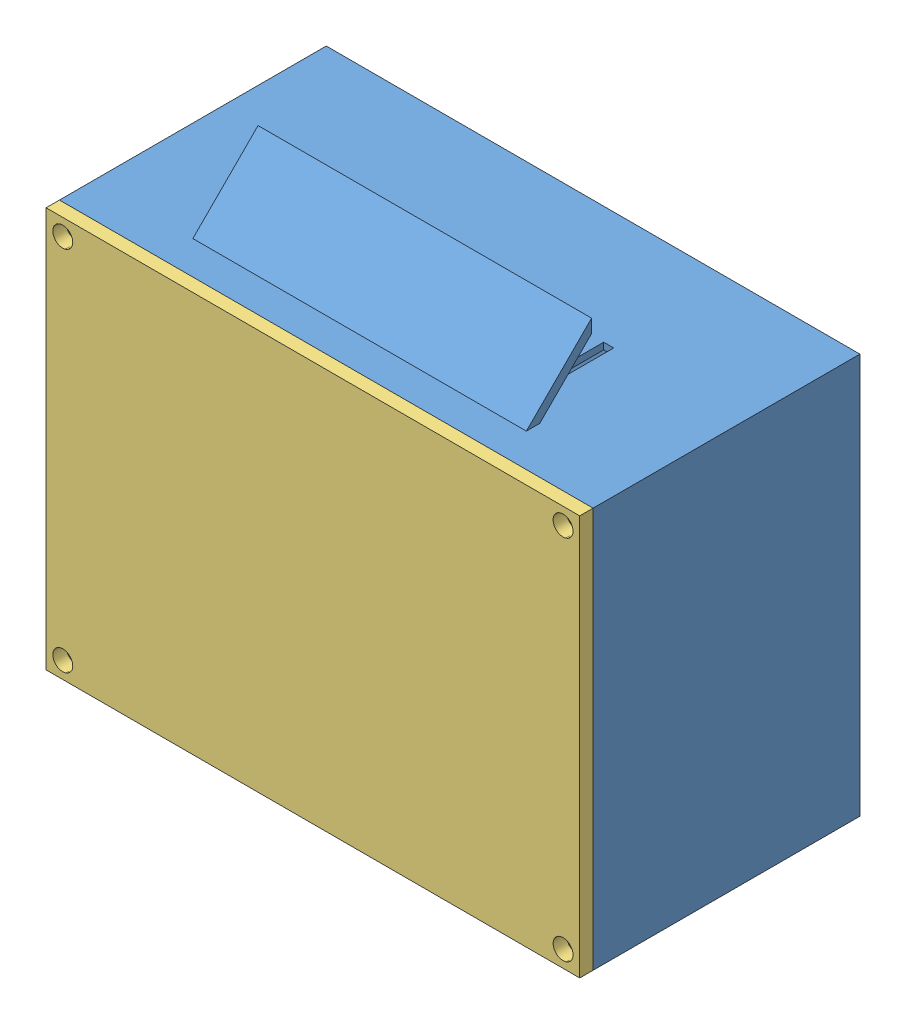
SolidWorks assembly ensamble de caja, configuration Predeterminado. Lengths in mm.
Overall size (81.33 79.56 42).
3 component instances, 3 part files, 2 mates.
Components (placement in the parent):
- proyecto case-1: proyecto case [Predeterminado] at (32.2877 -7.4744 -21.9408) size (80 79.56 40)
- conector-1: conector [Predeterminado] at (-6.0431 -27.4744 -11.9408) x (0 0 1) z (-1 0 0) size (7 7 3)
- tapadera de case-1: tapadera de case [Predeterminado] at (32.2877 -7.4744 18.0592) x (0 1 0) z (0 0 1) size (60 80 2)
Mates (geometry in assembly coordinates):
- Concéntrica1: concentric aligned: circle of proyecto case-1; circle of conector-1
- Coincidente3: coincident: point of proyecto case-1; point of tapadera de case-1
